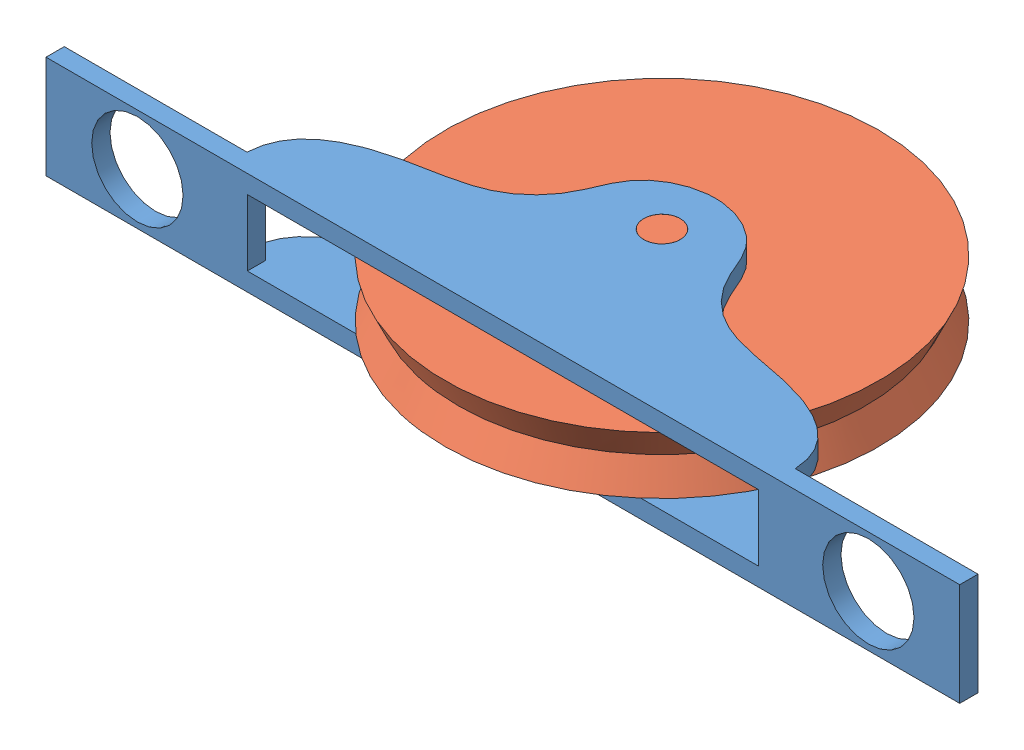
SolidWorks assembly Assem3, configuration Default. Lengths in mm.
Overall size (63.5 7.14 34.93).
2 component instances, 2 part files, 1 mates.
Components (placement in the parent):
- slot-1: slot [Default] at (25.1623 33.3922 53.9263) size (63.5 7.14 14.8)
- wheel-1: wheel [Default] at (25.1623 35.3766 44.1385) x (0 -1 0) z (-0.173033 0 0.984916) size (7.14 30.16 30.16)
Mates (geometry in assembly coordinates):
- Coincident1: coincident anti-aligned: circle of slot-1; circle of wheel-1
